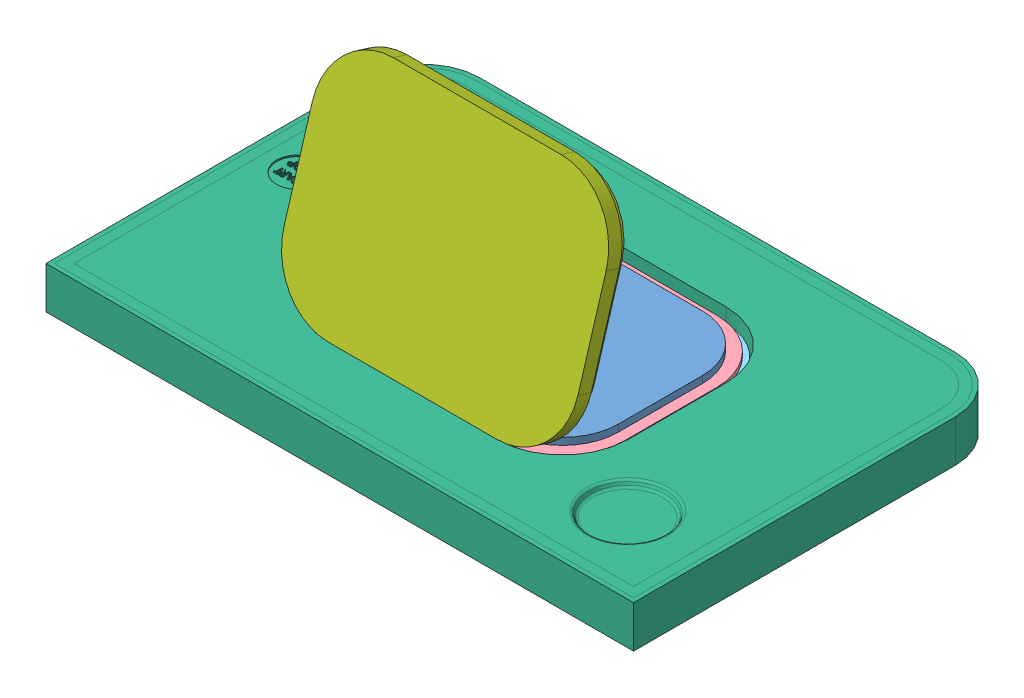
SolidWorks assembly Tray_Onshape, configuration Default. Lengths in mm.
Overall size (420 223.67 270).
15 component instances, 7 part files, 8 mates.
Components (placement in the parent):
- Food_Sample-1: Food_Sample [Default] at (-80.3287 -142.0613 114.0894) size (190 35 140)
- CAM_Assembly_v2-1: CAM_Assembly_v2 [Default] at (-130.5154 -115.1378 93.2027) size (243.6 55.89 193.6) (flexible)
  - SG90 - Micro Servo 9g - Tower Pro.1-1: SG90 - Micro Servo 9g - Tower Pro.1 [Peça] at (44.6867 -40.0376 -65.2633) x (-1 0 0) z (0 1 0) size (32.1 29.95 12.4)
  - SG90 - Micro Servo 9g - Tower Pro.1-2: SG90 - Micro Servo 9g - Tower Pro.1 [Peça] at (44.6867 -40.0376 107.0367) x (-1 0 0) z (0 -1 0) size (32.1 29.95 12.4)
  - SG90 - Micro Servo 9g - Tower Pro.1-3: SG90 - Micro Servo 9g - Tower Pro.1 [Peça] at (161.3367 -40.0376 15.3867) x (0 0 1) z (0 -1 0) size (32.1 29.95 12.4)
  - SG90 - Micro Servo 9g - Tower Pro.1-4: SG90 - Micro Servo 9g - Tower Pro.1 [Peça] at (-60.9633 -40.0376 15.3867) x (0 0 1) z (0 1 0) size (32.1 29.95 12.4)
  - Assem1^CAM_Assembly_v2-1: Assem1^CAM_Assembly_v2 [Default] at (-45.3437 -185.653 -223.8843) size (218 55.89 168) (virtual)
    - CAM-1: CAM [V2] at (189.0304 145.6154 234.121) x (0 0.123113 -0.992393) z (1 0 0) size (50 50 6.8)
    - CAM-2: CAM [V2] at (95.1804 145.6154 176.271) x (-0.992393 -0.123113 0) z (0 0 -1) size (50 50 6.8)
    - CAM-3: CAM [V2] at (95.1804 145.6154 313.271) x (0.992393 0.123113 0) z (0 0 1) size (50 50 6.8)
    - CAM-4: CAM [V2] at (2.0304 145.6154 234.121) x (0 -0.123113 0.992393) z (-1 0 0) size (50 50 6.8)
    - Food_Holder-1: Food_Holder [Default] at (95.5304 155.7295 244.771) size (205 46 155)
    - Servo_Holder_v2-1: Servo_Holder_v2 [Default] at (95.5304 135.6154 244.771) size (218 23 168)
- Tray_v1-1: Tray_v1 [Default] at (-80.3287 -138.0613 114.0894) x (-1 0 0) z (0 0 -1) size (420 70 270)
- Lid-1: Lid [Default] at (-80.3287 -66.3528 156.7587) x (-1 0 0) z (0 0.957586 -0.288146) size (210 18.6 160)
Mates (geometry in assembly coordinates):
- Coincident11: coincident aligned: line of Tray_v1-1 through (-20.3287 -138.0613 196.0894) axis (-1 0 0); line of Lid-1 through (-20.3287 -138.0613 196.0894) axis (-1 0 0)
- Width10: width anti-aligned: plane of Lid-1 through (24.6713 -61.4543 173.0377) normal (1 0 0); plane of Lid-1 through (-185.3287 -61.4543 173.0377) normal (-1 0 0); plane of Tray_v1-1 through (26.6713 -168.0613 114.0894) normal (-1 0 0); plane of Tray_v1-1 through (-187.3287 -168.0613 114.0894) normal (1 0 0)
- Width11: width anti-aligned: plane of CAM_Assembly_v2-1/Assem1^CAM_Assembly_v2-1/Servo_Holder_v2-1 through (23.1713 -145.1754 114.0894) normal (1 0 0); plane of CAM_Assembly_v2-1/Assem1^CAM_Assembly_v2-1/Servo_Holder_v2-1 through (-183.8287 -145.1754 114.0894) normal (-1 0 0); plane of Tray_v1-1 through (26.6713 -168.0613 114.0894) normal (-1 0 0); plane of Tray_v1-1 through (-187.3287 -168.0613 114.0894) normal (1 0 0)
- Width12: width anti-aligned: plane of CAM_Assembly_v2-1/Assem1^CAM_Assembly_v2-1/Servo_Holder_v2-1 through (-80.3287 -145.1754 35.5894) normal (0 0 -1); plane of CAM_Assembly_v2-1/Assem1^CAM_Assembly_v2-1/Servo_Holder_v2-1 through (-80.3287 -145.1754 192.5894) normal (0 0 1); plane of Tray_v1-1 through (-80.3287 -168.0613 32.0894) normal (0 0 1); plane of Tray_v1-1 through (-80.3287 -168.0613 196.0894) normal (0 0 -1)
- Coincident13: coincident anti-aligned: plane of Food_Sample-1 through (-80.3287 -142.0613 114.0894) normal (0 -1 0); plane of CAM_Assembly_v2-1/Assem1^CAM_Assembly_v2-1/Food_Holder-1 through (-80.3287 -142.0613 114.0894) normal (0 1 0)
- Width13: width anti-aligned: plane of Food_Sample-1 through (-80.3287 -137.0613 44.0894) normal (0 0 -1); plane of Food_Sample-1 through (-80.3287 -137.0613 184.0894) normal (0 0 1); plane of CAM_Assembly_v2-1/Assem1^CAM_Assembly_v2-1/Food_Holder-1 through (-80.3287 -150.0613 182.0894) normal (0 0 1); plane of CAM_Assembly_v2-1/Assem1^CAM_Assembly_v2-1/Food_Holder-1 through (-80.3287 -150.0613 46.0894) normal (0 0 -1)
- Width14: width anti-aligned: plane of Food_Sample-1 through (14.6713 -137.0613 114.0894) normal (1 0 0); plane of Food_Sample-1 through (-175.3287 -137.0613 114.0894) normal (-1 0 0); plane of CAM_Assembly_v2-1/Assem1^CAM_Assembly_v2-1/Servo_Holder_v2-1 through (-183.8287 -145.1754 114.0894) normal (-1 0 0); plane of CAM_Assembly_v2-1/Assem1^CAM_Assembly_v2-1/Servo_Holder_v2-1 through (23.1713 -145.1754 114.0894) normal (1 0 0)
- Distance1: distance = 10 mm anti-aligned: plane of CAM_Assembly_v2-1/Assem1^CAM_Assembly_v2-1/Food_Holder-1 through (-137.8287 -188.0613 81.5894) normal (0 -1 0); plane of Tray_v1-1 through (-140.3287 -198.0613 79.0894) normal (0 1 0)
